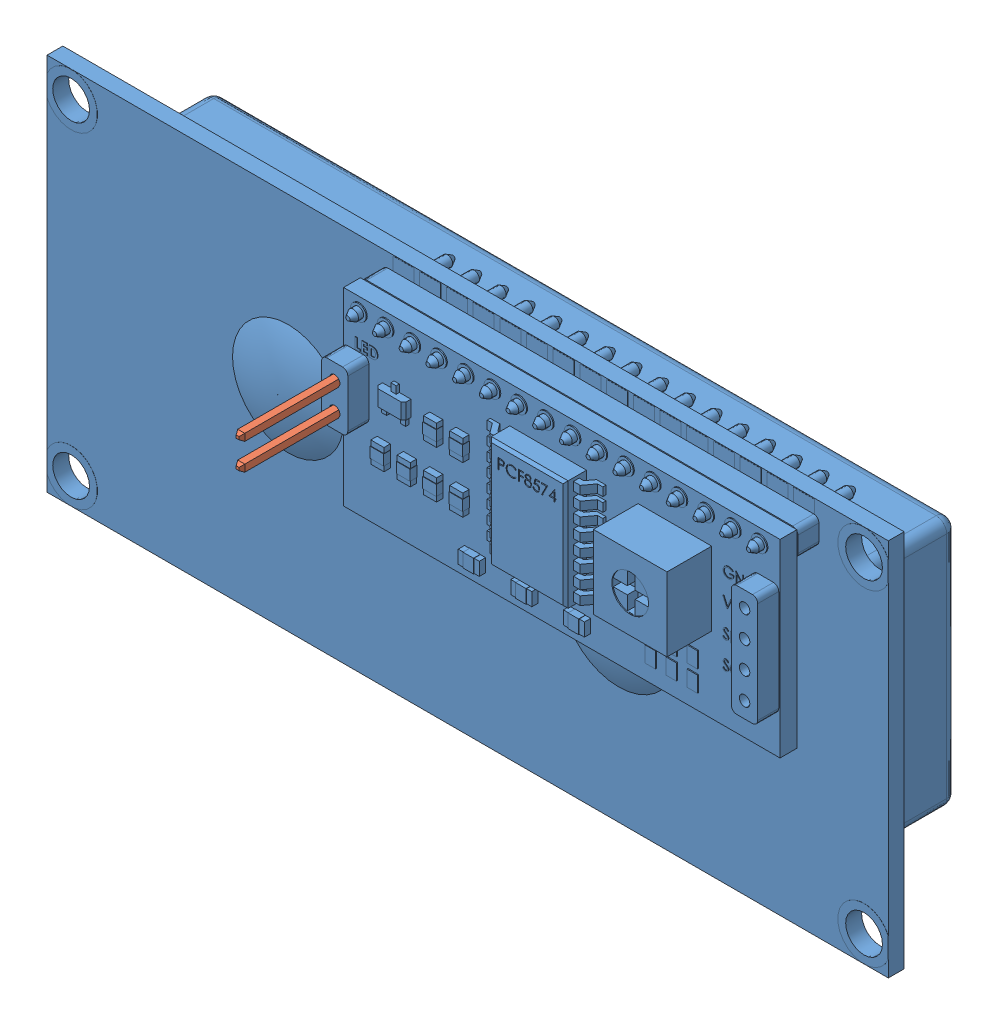
SolidWorks assembly User Library-LCD1602 with I2C, configuration Default. Lengths in mm.
Overall size (80 36 26.6).
4 component instances, 2 part files, 0 mates.
Components (placement in the parent):
- User Library-LCD1602 with I2C_Imported-1: User Library-LCD1602 with I2C_Imported [Default] at origin size (80 36 19.5)
- User Library-LCD1602 with I2C_User Library-1x4 TH Pitch 2_54mm-1: User Library-LCD1602 with I2C_User Library-1x4 TH Pitch 2_54mm [Default] at (-19.5 4.25 3.75) x (0 1 0) z (1 0 0) size (3.21 12.7 0.67)
  - User Library-LCD1602 with I2C_pin-1: User Library-LCD1602 with I2C_pin [Default] at (-1.29 -3.5 0.02) size (0.67 12.7 0.67)
  - User Library-LCD1602 with I2C_pin-2: User Library-LCD1602 with I2C_pin [Default] at (-3.83 -3.5 0.02) size (0.67 12.7 0.67)
